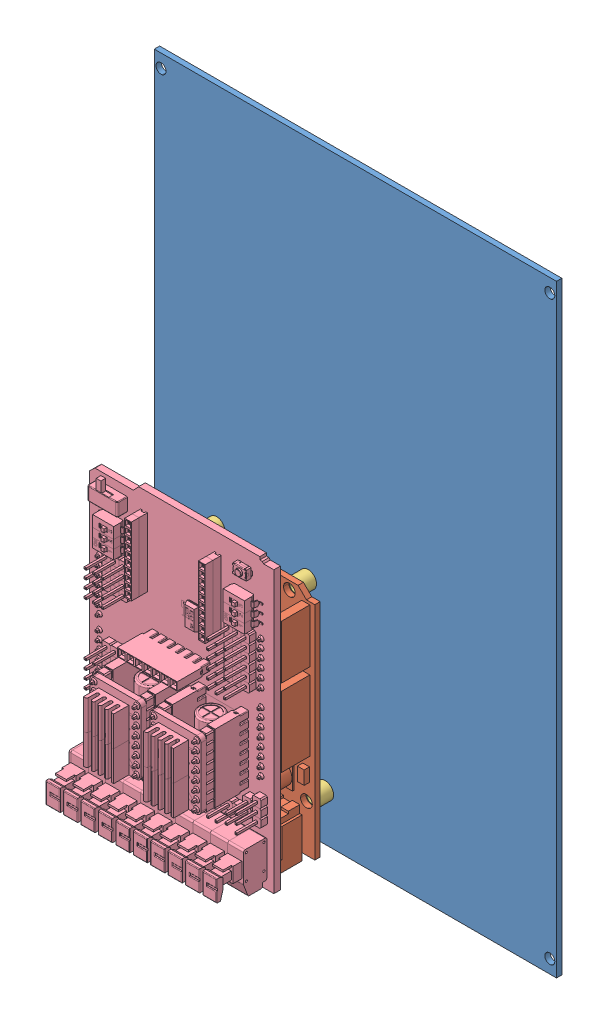
SolidWorks assembly pcb_assem, configuration Domyślna. Lengths in mm.
Overall size (120.3 186.5 40.01).
7 component instances, 4 part files, 14 mates.
Components (placement in the parent):
- pcb]-1: pcb] [Domyślna] at (15.285 13.4117 -0.8) size (120 180 1.6)
- Arduino-UNO.stp-2: Arduino-UNO.stp [Domyślna] at (-17.965 -43.5883 4.8) x (-1 0 0) z (0 1 0) size (53.5 14.9 75)
- distance_4mm-1: distance_4mm [Domyślna] at (6.285 -62.5883 0.8) x (0.592454 0.805604 0) z (0 0 1) size (5 5 4)
- distance_4mm-2: distance_4mm [Domyślna] at (1.185 -10.5883 0.8) size (5 5 4)
- distance_4mm-3: distance_4mm [Domyślna] at (-26.115 -10.5883 0.8) size (5 5 4)
- distance_4mm-4: distance_4mm [Domyślna] at (-42.215 -61.3883 0.8) size (5 5 4)
- DFRobot stepper motor DRI0023.step-1: DFRobot stepper motor DRI0023.step [Domyślna] at (-17.5157 -35.4605 19.8216) x (0 -1 0) z (0 0 -1) size (85 55 29.64)
Mates (geometry in assembly coordinates):
- Concentric1: concentric anti-aligned: cylinder of Arduino-UNO.stp-2 through (-42.215 -61.3883 14.1893) axis (0 0 1) radius 1.75; cylinder of distance_4mm-4 through (-42.215 -61.3883 14.1893) axis (0 0 -1) radius 1.5
- Concentric2: concentric anti-aligned: cylinder of Arduino-UNO.stp-2 through (6.285 -62.5883 14.1893) axis (0 0 1) radius 1.75; cylinder of distance_4mm-1 through (6.285 -62.5883 14.1893) axis (0 0 -1) radius 1.5
- Concentric3: concentric anti-aligned: cylinder of Arduino-UNO.stp-2 through (1.185 -10.5883 14.1893) axis (0 0 1) radius 1.75; cylinder of distance_4mm-2 through (1.185 -10.5883 14.1893) axis (0 0 -1) radius 1.5
- Concentric4: concentric anti-aligned: cylinder of Arduino-UNO.stp-2 through (-26.115 -10.5883 14.1893) axis (0 0 1) radius 1.75; cylinder of distance_4mm-3 through (-26.115 -10.5883 14.1893) axis (0 0 -1) radius 1.5
- Concentric5: concentric anti-aligned: cylinder of Arduino-UNO.stp-2 through (-42.215 -61.3883 4.8) axis (0 0 1) radius 1.75; cylinder of distance_4mm-4 through (-42.215 -61.3883 4.8) axis (0 0 -1) radius 1.5
- Coincident3: coincident aligned: plane of distance_4mm-1 through (6.285 -62.5883 4.8) normal (0 0 1); plane of distance_4mm-4 through (-42.215 -61.3883 4.8) normal (0 0 1)
- Coincident4: coincident aligned: plane of distance_4mm-2 through (1.185 -10.5883 4.8) normal (0 0 1); plane of distance_4mm-3 through (-26.115 -10.5883 4.8) normal (0 0 1)
- Coincident5: coincident aligned: plane of distance_4mm-3 through (-26.115 -10.5883 4.8) normal (0 0 1); plane of distance_4mm-4 through (-42.215 -61.3883 4.8) normal (0 0 1)
- Coincident6: coincident anti-aligned: plane of Arduino-UNO.stp-2 through (-17.965 -43.5883 4.8) normal (0 0 -1); plane of distance_4mm-4 through (-42.215 -61.3883 4.8) normal (0 0 1)
- Coincident7: coincident aligned: plane of pcb]-1 through (75.285 -76.5883 0.8) normal (0 -1 0); plane of Arduino-UNO.stp-2 through (-44.715 -76.5883 4.8) normal (0 -1 0)
- Coincident8: coincident aligned: plane of pcb]-1 through (-44.715 -76.5883 0.8) normal (-1 0 0); plane of Arduino-UNO.stp-2 through (-44.715 -10.5883 4.8) normal (-1 0 0)
- Coincident9: coincident anti-aligned: plane of pcb]-1 through (15.285 13.4117 0.8) normal (0 0 1); plane of distance_4mm-4 through (-42.215 -61.3883 0.8) normal (0 0 -1)
- Coincident10: coincident: plane of Arduino-UNO.stp-2 through (5.585 -49.7383 14.9) normal (0 1 0); plane of DFRobot stepper motor DRI0023.step-1 through (6.585 -49.7383 18.4566) normal (0 -1 0)
- Coincident11: coincident anti-aligned: plane of Arduino-UNO.stp-2 through (6.585 -49.7383 14.9) normal (-1 0 0); plane of DFRobot stepper motor DRI0023.step-1 through (6.585 -49.1033 18.4566) normal (1 0 0)
